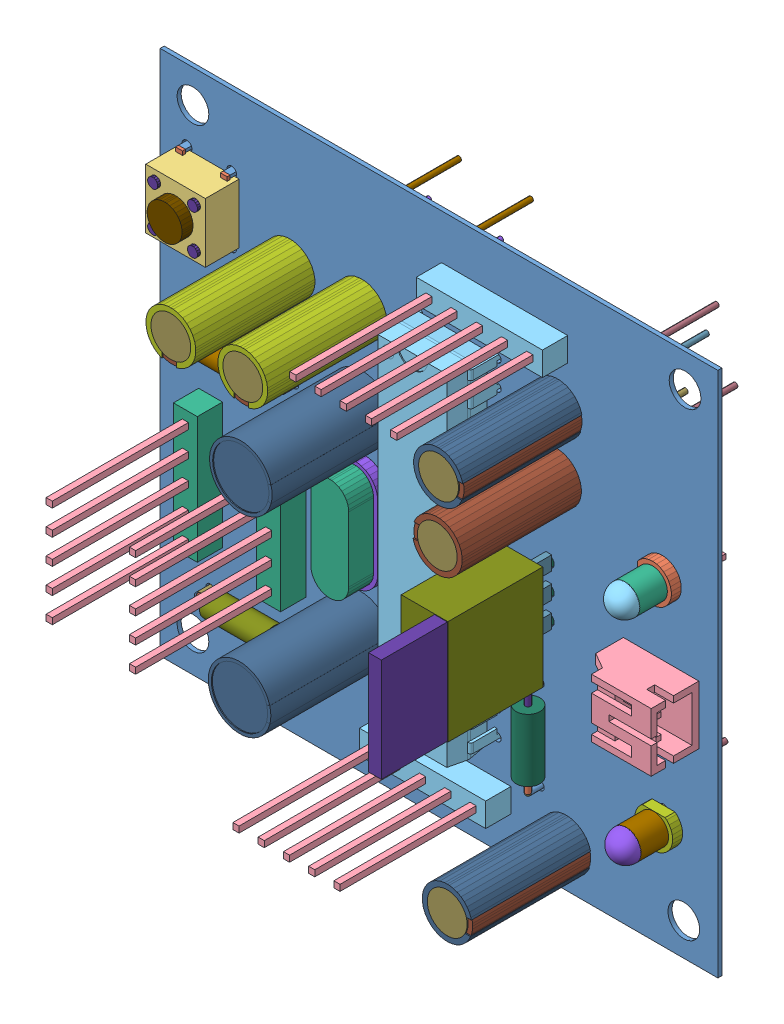
SolidWorks assembly project_1, configuration Default. Lengths in mm.
Overall size (56.13 52.96 36.7).
255 component instances, 53 part files, 0 mates.
Components (placement in the parent):
- project_1.step-1: project_1.step [Default] at origin size (56.13 52.96 36.7)
  - Board.step-1: Board.step [Default] at origin size (56.13 52.96 0.41)
    - Open CASCADE STEP translator 7.5 1.1.1.step-1: Open CASCADE STEP translator 7.5 1.1.1.step [Default] at (0 0 -0.4115) size (56.13 52.96 0.41)
  - LED-BT.step-1: LED-BT.step [Default] at origin size (3.42 3.82 10.3)
    - 6102661152.step-1: 6102661152.step [Default] at (50.736 32.131 0) size (3.42 3.82 1)
      - Extruded.step-1: Extruded.step [Default] at origin size (3.42 3.82 1)
    - 6102654272.step-1: 6102654272.step [Default] at (49.4059 32.1309 -4) size (0.5 0.5 4)
      - Extruded-0.step-1: Extruded-0.step [Default] at origin size (0.5 0.5 4)
    - 6102665392.step-1: 6102665392.step [Default] at (51.6859 32.1309 -5) size (0.5 0.5 5)
      - Extruded-1.step-1: Extruded-1.step [Default] at origin size (0.5 0.5 5)
    - 6102654592.step-1: 6102654592.step [Default] at (50.5459 32.131 3.8) x (-1 0 0) z (0 0 1) size (3 3 3)
      - Sphere.step-1: Sphere.step [Default] at origin size (3 3 3)
    - 6102659712.step-1: 6102659712.step [Default] at (50.5459 32.1309 1) x (-1 0 0) z (0 0 1) size (3 3 2.8)
      - Cylinder.step-1: Cylinder.step [Default] at origin size (3 3 2.8)
  - Buzzer.step-1: Buzzer.step [Default] at origin size (3.82 3.42 10.3)
    - 6102655392.step-1: 6102655392.step [Default] at (50.673 10.605 0) size (3.82 3.42 1)
      - Extruded-2.step-1: Extruded-2.step [Default] at origin size (3.82 3.42 1)
    - 6102654272.step-1: 6102654272.step [Default] at (50.6729 11.9351 -4) size (0.5 0.5 4)
      - Extruded-0.step-1: Extruded-0.step [Default] at origin size (0.5 0.5 4)
    - 6102665392.step-1: 6102665392.step [Default] at (50.6729 9.6551 -5) size (0.5 0.5 5)
      - Extruded-1.step-1: Extruded-1.step [Default] at origin size (0.5 0.5 5)
    - 6102665072.step-1: 6102665072.step [Default] at (50.673 10.7951 3.8) x (0 1 0) z (0 0 1) size (3 3 3)
      - Sphere-3.step-1: Sphere-3.step [Default] at origin size (3 3 3)
    - 6102664912.step-1: 6102664912.step [Default] at (50.6729 10.7951 1) x (0 1 0) z (0 0 1) size (3 3 2.8)
      - Cylinder-4.step-1: Cylinder-4.step [Default] at origin size (3 3 2.8)
  - C10.step-1: C10.step [Default] at origin size (4.95 5 29.01)
    - 6102661072.step-1: 6102661072.step [Default] at (40.8605 4.064 0.01) size (4.94 5 12)
      - Extruded-5.step-1: Extruded-5.step [Default] at origin size (4.94 5 12)
    - 6102666112.step-1: 6102666112.step [Default] at (40.894 4.064 0.02) size (4.9 4.9 11.87)
      - Extruded-6.step-1: Extruded-6.step [Default] at origin size (4.9 4.9 11.87)
    - 6102655472.step-1: 6102655472.step [Default] at (40.8939 4.0639 0) size (4 4 12)
      - Extruded-7.step-1: Extruded-7.step [Default] at origin size (4 4 12)
    - 6102661632.step-1: 6102661632.step [Default] at (39.8941 4.0641 -17) x (1 0 0) z (0 0 1) size (0.5 0.5 17)
      - Cylinder-8.step-1: Cylinder-8.step [Default] at origin size (0.5 0.5 17)
    - 6102653872.step-1: 6102653872.step [Default] at (41.8941 4.0641 -14) x (1 0 0) z (0 0 1) size (0.5 0.5 14)
      - Cylinder-9.step-1: Cylinder-9.step [Default] at origin size (0.5 0.5 14)
  - R5.step-1: R5.step [Default] at origin size (2.4 9.55 4.4)
    - 6102655552.step-1: 6102655552.step [Default] at (38.2269 15.4689 1.2) x (1 0 0) z (0 -1 0) size (2.4 2.4 6.3)
      - Cylinder-10.step-1: Cylinder-10.step [Default] at origin size (2.4 2.4 6.3)
    - 6102659232.step-1: 6102659232.step [Default] at (38.227 16.819 1.2) x (0 -1 0) z (0 0 1) size (0.55 0.55 0.55)
      - Sphere-11.step-1: Sphere-11.step [Default] at origin size (0.55 0.55 0.55)
    - 6102664992.step-1: 6102664992.step [Default] at (38.2268 16.8192 1.2) x (0 0 -1) z (0 -1 0) size (0.55 0.55 1.35)
      - Cylinder-12.step-1: Cylinder-12.step [Default] at origin size (0.55 0.55 1.35)
    - 6102653712.step-1: 6102653712.step [Default] at (38.2268 16.8192 -2) x (0 -1 0) z (0 0 1) size (0.55 0.55 3.2)
      - Cylinder-13.step-1: Cylinder-13.step [Default] at origin size (0.55 0.55 3.2)
    - 6102659872.step-1: 6102659872.step [Default] at (38.2272 7.8189 -2) x (0 1 0) z (0 0 1) size (0.55 0.55 3.2)
      - Cylinder-14.step-1: Cylinder-14.step [Default] at origin size (0.55 0.55 3.2)
    - 6102653392.step-1: 6102653392.step [Default] at (38.2272 7.8189 1.2) x (0 0 -1) z (0 1 0) size (0.55 0.55 1.35)
      - Cylinder-15.step-1: Cylinder-15.step [Default] at origin size (0.55 0.55 1.35)
    - 6102659072.step-1: 6102659072.step [Default] at (38.227 7.819 1.2) x (0 1 0) z (0 0 1) size (0.55 0.55 0.55)
      - Sphere-16.step-1: Sphere-16.step [Default] at origin size (0.55 0.55 0.55)
  - HC-SR04-3.step-1: HC-SR04-3.step [Default] at origin size (12.7 2.4 19.29)
    - 6102658592.step-1: 6102658592.step [Default] at (23.8759 5.0799 -3.05) size (0.62 0.62 19.29)
      - Extruded-17.step-1: Extruded-17.step [Default] at origin size (0.62 0.62 19.29)
    - 6102658592.step-2: 6102658592.step [Default] at (26.4159 5.0799 -3.05) size (0.62 0.62 19.29)
      - Extruded-17.step-1: Extruded-17.step [Default] at origin size (0.62 0.62 19.29)
    - 6102658592.step-3: 6102658592.step [Default] at (34.0359 5.0799 -3.05) size (0.62 0.62 19.29)
      - Extruded-17.step-1: Extruded-17.step [Default] at origin size (0.62 0.62 19.29)
    - 6102658592.step-4: 6102658592.step [Default] at (31.4959 5.0799 -3.05) size (0.62 0.62 19.29)
      - Extruded-17.step-1: Extruded-17.step [Default] at origin size (0.62 0.62 19.29)
    - 6102658592.step-5: 6102658592.step [Default] at (28.956 5.08 -3.05) size (0.62 0.62 19.29)
      - Extruded-17.step-1: Extruded-17.step [Default] at origin size (0.62 0.62 19.29)
    - 6102655632.step-1: 6102655632.step [Default] at (28.956 5.08 0) size (12.7 2.4 2.54)
      - Extruded-18.step-1: Extruded-18.step [Default] at origin size (12.7 2.4 2.54)
  - HC-SR04-2.step-1: HC-SR04-2.step [Default] at origin size (12.7 2.4 19.29)
    - 6102658592.step-1: 6102658592.step [Default] at (39.7511 47.2441 -3.05) size (0.62 0.62 19.29)
      - Extruded-17.step-1: Extruded-17.step [Default] at origin size (0.62 0.62 19.29)
    - 6102658592.step-2: 6102658592.step [Default] at (37.2111 47.2441 -3.05) size (0.62 0.62 19.29)
      - Extruded-17.step-1: Extruded-17.step [Default] at origin size (0.62 0.62 19.29)
    - 6102658592.step-3: 6102658592.step [Default] at (29.5911 47.2441 -3.05) size (0.62 0.62 19.29)
      - Extruded-17.step-1: Extruded-17.step [Default] at origin size (0.62 0.62 19.29)
    - 6102658592.step-4: 6102658592.step [Default] at (32.1311 47.2441 -3.05) size (0.62 0.62 19.29)
      - Extruded-17.step-1: Extruded-17.step [Default] at origin size (0.62 0.62 19.29)
    - 6102658592.step-5: 6102658592.step [Default] at (34.671 47.244 -3.05) size (0.62 0.62 19.29)
      - Extruded-17.step-1: Extruded-17.step [Default] at origin size (0.62 0.62 19.29)
    - 6102655632.step-1: 6102655632.step [Default] at (34.671 47.244 0) size (12.7 2.4 2.54)
      - Extruded-18.step-1: Extruded-18.step [Default] at origin size (12.7 2.4 2.54)
  - Y.step-1: Y.step [Default] at origin size (4.65 11.05 17)
    - 6102661872.step-1: 6102661872.step [Default] at (20.574 22.2619 0) size (3.8 10.35 3.5)
      - Extruded-19.step-1: Extruded-19.step [Default] at origin size (3.8 10.35 3.5)
    - 6102648432.step-1: 6102648432.step [Default] at (20.5739 19.8121 -13.5) x (0 1 0) z (0 0 1) size (0.45 0.45 13.5)
      - Cylinder-20.step-1: Cylinder-20.step [Default] at origin size (0.45 0.45 13.5)
    - 6102648432.step-2: 6102648432.step [Default] at (20.5739 24.7121 -13.5) x (0 1 0) z (0 0 1) size (0.45 0.45 13.5)
      - Cylinder-20.step-1: Cylinder-20.step [Default] at origin size (0.45 0.45 13.5)
    - 6102647952.step-1: 6102647952.step [Default] at (20.574 22.2619 0) size (4.65 11.05 1)
      - Extruded-21.step-1: Extruded-21.step [Default] at origin size (4.65 11.05 1)
  - R4.step-1: R4.step [Default] at origin size (9.55 2.4 4.4)
    - 6102655152.step-1: 6102655152.step [Default] at (5.8671 30.4799 1.2) x (0 1 0) z (1 0 0) size (2.4 2.4 6.3)
      - Cylinder-22.step-1: Cylinder-22.step [Default] at origin size (2.4 2.4 6.3)
    - 6102653312.step-1: 6102653312.step [Default] at (4.517 30.48 1.2) x (1 0 0) z (0 0 1) size (0.55 0.55 0.55)
      - Sphere-23.step-1: Sphere-23.step [Default] at origin size (0.55 0.55 0.55)
    - 6102664512.step-1: 6102664512.step [Default] at (4.5169 30.4798 1.2) x (0 0 -1) z (1 0 0) size (0.55 0.55 1.35)
      - Cylinder-24.step-1: Cylinder-24.step [Default] at origin size (0.55 0.55 1.35)
    - 6102659152.step-1: 6102659152.step [Default] at (4.5169 30.4798 -2) x (1 0 0) z (0 0 1) size (0.55 0.55 3.2)
      - Cylinder-25.step-1: Cylinder-25.step [Default] at origin size (0.55 0.55 3.2)
    - 6102660352.step-1: 6102660352.step [Default] at (13.5171 30.4802 -2) x (-1 0 0) z (0 0 1) size (0.55 0.55 3.2)
      - Cylinder-26.step-1: Cylinder-26.step [Default] at origin size (0.55 0.55 3.2)
    - 6102658992.step-1: 6102658992.step [Default] at (13.5171 30.4802 1.2) x (0 0 -1) z (-1 0 0) size (0.55 0.55 1.35)
      - Cylinder-27.step-1: Cylinder-27.step [Default] at origin size (0.55 0.55 1.35)
    - 6102664672.step-1: 6102664672.step [Default] at (13.517 30.48 1.2) x (-1 0 0) z (0 0 1) size (0.55 0.55 0.55)
      - Sphere-28.step-1: Sphere-28.step [Default] at origin size (0.55 0.55 0.55)
  - R3.step-1: R3.step [Default] at origin size (9.55 2.4 4.4)
    - 6102653312.step-1: 6102653312.step [Default] at (5.025 8.382 1.2) x (1 0 0) z (0 0 1) size (0.55 0.55 0.55)
      - Sphere-23.step-1: Sphere-23.step [Default] at origin size (0.55 0.55 0.55)
    - 6102664512.step-1: 6102664512.step [Default] at (5.0249 8.3818 1.2) x (0 0 -1) z (1 0 0) size (0.55 0.55 1.35)
      - Cylinder-24.step-1: Cylinder-24.step [Default] at origin size (0.55 0.55 1.35)
    - 6102659152.step-1: 6102659152.step [Default] at (5.0249 8.3818 -2) x (1 0 0) z (0 0 1) size (0.55 0.55 3.2)
      - Cylinder-25.step-1: Cylinder-25.step [Default] at origin size (0.55 0.55 3.2)
    - 6102660352.step-1: 6102660352.step [Default] at (14.0251 8.3822 -2) x (-1 0 0) z (0 0 1) size (0.55 0.55 3.2)
      - Cylinder-26.step-1: Cylinder-26.step [Default] at origin size (0.55 0.55 3.2)
    - 6102658992.step-1: 6102658992.step [Default] at (14.0251 8.3822 1.2) x (0 0 -1) z (-1 0 0) size (0.55 0.55 1.35)
      - Cylinder-27.step-1: Cylinder-27.step [Default] at origin size (0.55 0.55 1.35)
    - 6102664672.step-1: 6102664672.step [Default] at (14.025 8.382 1.2) x (-1 0 0) z (0 0 1) size (0.55 0.55 0.55)
      - Sphere-28.step-1: Sphere-28.step [Default] at origin size (0.55 0.55 0.55)
    - 6102662752.step-1: 6102662752.step [Default] at (12.6749 8.3821 1.2) x (0 -1 0) z (-1 0 0) size (2.4 2.4 6.3)
      - Cylinder-29.step-1: Cylinder-29.step [Default] at origin size (2.4 2.4 6.3)
  - R1.step-1: R1.step [Default] at origin size (9.55 2.4 4.4)
    - 6102664672.step-1: 6102664672.step [Default] at (13.517 34.671 1.2) x (-1 0 0) z (0 0 1) size (0.55 0.55 0.55)
      - Sphere-28.step-1: Sphere-28.step [Default] at origin size (0.55 0.55 0.55)
    - 6102658992.step-1: 6102658992.step [Default] at (13.5171 34.6712 1.2) x (0 0 -1) z (-1 0 0) size (0.55 0.55 1.35)
      - Cylinder-27.step-1: Cylinder-27.step [Default] at origin size (0.55 0.55 1.35)
    - 6102660352.step-1: 6102660352.step [Default] at (13.5171 34.6712 -2) x (-1 0 0) z (0 0 1) size (0.55 0.55 3.2)
      - Cylinder-26.step-1: Cylinder-26.step [Default] at origin size (0.55 0.55 3.2)
    - 6102659152.step-1: 6102659152.step [Default] at (4.5169 34.6708 -2) x (1 0 0) z (0 0 1) size (0.55 0.55 3.2)
      - Cylinder-25.step-1: Cylinder-25.step [Default] at origin size (0.55 0.55 3.2)
    - 6102664512.step-1: 6102664512.step [Default] at (4.5169 34.6708 1.2) x (0 0 -1) z (1 0 0) size (0.55 0.55 1.35)
      - Cylinder-24.step-1: Cylinder-24.step [Default] at origin size (0.55 0.55 1.35)
    - 6102653312.step-1: 6102653312.step [Default] at (4.517 34.671 1.2) x (1 0 0) z (0 0 1) size (0.55 0.55 0.55)
      - Sphere-23.step-1: Sphere-23.step [Default] at origin size (0.55 0.55 0.55)
    - 6102655152.step-1: 6102655152.step [Default] at (5.8671 34.6709 1.2) x (0 1 0) z (1 0 0) size (2.4 2.4 6.3)
      - Cylinder-22.step-1: Cylinder-22.step [Default] at origin size (2.4 2.4 6.3)
  - Push button.step-1: Push button.step [Default] at origin size (6 6.8 8)
    - 6102654192.step-1: 6102654192.step [Default] at (2.953 40.545 0.1) size (1 1 3.6)
      - Extruded-30.step-1: Extruded-30.step [Default] at origin size (1 1 3.6)
    - 6102654192.step-2: 6102654192.step [Default] at (6.953 44.545 0.1) size (1 1 3.6)
      - Extruded-30.step-1: Extruded-30.step [Default] at origin size (1 1 3.6)
    - 6102654192.step-3: 6102654192.step [Default] at (6.953 40.545 0.1) size (1 1 3.6)
      - Extruded-30.step-1: Extruded-30.step [Default] at origin size (1 1 3.6)
    - 6102654192.step-4: 6102654192.step [Default] at (2.953 44.545 0.1) size (1 1 3.6)
      - Extruded-30.step-1: Extruded-30.step [Default] at origin size (1 1 3.6)
    - 6102662512.step-1: 6102662512.step [Default] at (4.9531 42.5449 0.1) size (3.5 3.5 4.4)
      - Extruded-31.step-1: Extruded-31.step [Default] at origin size (3.5 3.5 4.4)
    - 6102656752.step-1: 6102656752.step [Default] at (2.7031 45.7951 -3.5) size (0.7 0.3 4)
      - Extruded-32.step-1: Extruded-32.step [Default] at origin size (0.7 0.3 4)
    - 6102654672.step-1: 6102654672.step [Default] at (2.7031 45.6455 0.5) size (0.7 0.6 0.3)
      - Extruded-33.step-1: Extruded-33.step [Default] at origin size (0.7 0.6 0.3)
    - 6102656752.step-2: 6102656752.step [Default] at (7.2029 39.2949 -3.5) size (0.7 0.3 4)
      - Extruded-32.step-1: Extruded-32.step [Default] at origin size (0.7 0.3 4)
    - 6102654672.step-2: 6102654672.step [Default] at (7.2029 39.4445 0.5) size (0.7 0.6 0.3)
      - Extruded-33.step-1: Extruded-33.step [Default] at origin size (0.7 0.6 0.3)
    - 6102656752.step-3: 6102656752.step [Default] at (7.2029 45.7951 -3.5) size (0.7 0.3 4)
      - Extruded-32.step-1: Extruded-32.step [Default] at origin size (0.7 0.3 4)
    - 6102654672.step-3: 6102654672.step [Default] at (7.2029 45.6455 0.5) size (0.7 0.6 0.3)
      - Extruded-33.step-1: Extruded-33.step [Default] at origin size (0.7 0.6 0.3)
    - 6102654672.step-4: 6102654672.step [Default] at (2.7031 39.4445 0.5) size (0.7 0.6 0.3)
      - Extruded-33.step-1: Extruded-33.step [Default] at origin size (0.7 0.6 0.3)
    - 6102656752.step-4: 6102656752.step [Default] at (2.7031 39.2949 -3.5) size (0.7 0.3 4)
      - Extruded-32.step-1: Extruded-32.step [Default] at origin size (0.7 0.3 4)
    - 6102660032.step-1: 6102660032.step [Default] at (4.953 42.545 0) size (6 6 3.4)
      - Extruded-34.step-1: Extruded-34.step [Default] at origin size (6 6 3.4)
  - POWER.step-1: POWER.step [Default] at origin size (7.6 5.9 8.2)
    - S2B-PH-K-S.step-1: S2B-PH-K-S.step [Default] at (45.2688 29.7212 6) x (0 1 0) z (1 0 0) size (5.9 8.2 7.6)
  - Microcontroller.step-1: Microcontroller.step [Default] at origin size (7.9 34.67 8)
    - 6105365808.step-1: 6105365808.step [Default] at (29.972 26.416 0) x (1 0 0) z (0 -1 0) size (7.9 8 34.67)
  - HC-SR04-1.step-1: HC-SR04-1.step [Default] at origin size (2.4 12.7 19.29)
    - 6102658192.step-1: 6102658192.step [Default] at (13.462 18.796 0) size (2.4 12.7 2.54)
      - Extruded-35.step-1: Extruded-35.step [Default] at origin size (2.4 12.7 2.54)
    - 6102658592.step-1: 6102658592.step [Default] at (13.462 18.796 -3.05) size (0.62 0.62 19.29)
      - Extruded-17.step-1: Extruded-17.step [Default] at origin size (0.62 0.62 19.29)
    - 6102658592.step-2: 6102658592.step [Default] at (13.4621 21.3359 -3.05) size (0.62 0.62 19.29)
      - Extruded-17.step-1: Extruded-17.step [Default] at origin size (0.62 0.62 19.29)
    - 6102658592.step-3: 6102658592.step [Default] at (13.4621 23.8759 -3.05) size (0.62 0.62 19.29)
      - Extruded-17.step-1: Extruded-17.step [Default] at origin size (0.62 0.62 19.29)
    - 6102658592.step-4: 6102658592.step [Default] at (13.4621 16.2559 -3.05) size (0.62 0.62 19.29)
      - Extruded-17.step-1: Extruded-17.step [Default] at origin size (0.62 0.62 19.29)
    - 6102658592.step-5: 6102658592.step [Default] at (13.4621 13.7159 -3.05) size (0.62 0.62 19.29)
      - Extruded-17.step-1: Extruded-17.step [Default] at origin size (0.62 0.62 19.29)
  - HC-05.step-1: HC-05.step [Default] at origin size (2.4 12.7 19.29)
    - 6102658192.step-1: 6102658192.step [Default] at (5.08 18.923 0) size (2.4 12.7 2.54)
      - Extruded-35.step-1: Extruded-35.step [Default] at origin size (2.4 12.7 2.54)
    - 6102658592.step-1: 6102658592.step [Default] at (5.08 18.923 -3.05) size (0.62 0.62 19.29)
      - Extruded-17.step-1: Extruded-17.step [Default] at origin size (0.62 0.62 19.29)
    - 6102658592.step-2: 6102658592.step [Default] at (5.0801 21.4629 -3.05) size (0.62 0.62 19.29)
      - Extruded-17.step-1: Extruded-17.step [Default] at origin size (0.62 0.62 19.29)
    - 6102658592.step-3: 6102658592.step [Default] at (5.0801 24.0029 -3.05) size (0.62 0.62 19.29)
      - Extruded-17.step-1: Extruded-17.step [Default] at origin size (0.62 0.62 19.29)
    - 6102658592.step-4: 6102658592.step [Default] at (5.0801 16.3829 -3.05) size (0.62 0.62 19.29)
      - Extruded-17.step-1: Extruded-17.step [Default] at origin size (0.62 0.62 19.29)
    - 6102658592.step-5: 6102658592.step [Default] at (5.0801 13.8429 -3.05) size (0.62 0.62 19.29)
      - Extruded-17.step-1: Extruded-17.step [Default] at origin size (0.62 0.62 19.29)
  - C8.step-1: C8.step [Default] at origin size (5 4.95 29.01)
    - 6102655472.step-1: 6102655472.step [Default] at (20.3199 40.4971 0) size (4 4 12)
      - Extruded-7.step-1: Extruded-7.step [Default] at origin size (4 4 12)
    - 6102666112.step-1: 6102666112.step [Default] at (20.32 40.497 0.02) size (4.9 4.9 11.87)
      - Extruded-6.step-1: Extruded-6.step [Default] at origin size (4.9 4.9 11.87)
    - 6102665232.step-1: 6102665232.step [Default] at (20.32 40.5305 0.01) size (5 4.94 12)
      - Extruded-36.step-1: Extruded-36.step [Default] at origin size (5 4.94 12)
    - 6102665152.step-1: 6102665152.step [Default] at (20.3201 39.4969 -14) x (0 -1 0) z (0 0 1) size (0.5 0.5 14)
      - Cylinder-37.step-1: Cylinder-37.step [Default] at origin size (0.5 0.5 14)
    - 6102655952.step-1: 6102655952.step [Default] at (20.3201 41.4969 -17) x (0 -1 0) z (0 0 1) size (0.5 0.5 17)
      - Cylinder-38.step-1: Cylinder-38.step [Default] at origin size (0.5 0.5 17)
  - C5.step-1: C5.step [Default] at origin size (4.95 5 29.01)
    - 6102655472.step-1: 6102655472.step [Default] at (40.0209 41.6559 0) size (4 4 12)
      - Extruded-7.step-1: Extruded-7.step [Default] at origin size (4 4 12)
    - 6102666112.step-1: 6102666112.step [Default] at (40.021 41.656 0.02) size (4.9 4.9 11.87)
      - Extruded-6.step-1: Extruded-6.step [Default] at origin size (4.9 4.9 11.87)
    - 6102661072.step-1: 6102661072.step [Default] at (39.9875 41.656 0.01) size (4.94 5 12)
      - Extruded-5.step-1: Extruded-5.step [Default] at origin size (4.94 5 12)
    - 6102653872.step-1: 6102653872.step [Default] at (41.0211 41.6561 -14) x (1 0 0) z (0 0 1) size (0.5 0.5 14)
      - Cylinder-9.step-1: Cylinder-9.step [Default] at origin size (0.5 0.5 14)
    - 6102661632.step-1: 6102661632.step [Default] at (39.0211 41.6561 -17) x (1 0 0) z (0 0 1) size (0.5 0.5 17)
      - Cylinder-8.step-1: Cylinder-8.step [Default] at origin size (0.5 0.5 17)
  - C4.step-1: C4.step [Default] at origin size (5 4.95 29.01)
    - 6102665232.step-1: 6102665232.step [Default] at (13.081 40.4195 0.01) size (5 4.94 12)
      - Extruded-36.step-1: Extruded-36.step [Default] at origin size (5 4.94 12)
    - 6102666112.step-1: 6102666112.step [Default] at (13.081 40.386 0.02) size (4.9 4.9 11.87)
      - Extruded-6.step-1: Extruded-6.step [Default] at origin size (4.9 4.9 11.87)
    - 6102655472.step-1: 6102655472.step [Default] at (13.0809 40.3861 0) size (4 4 12)
      - Extruded-7.step-1: Extruded-7.step [Default] at origin size (4 4 12)
    - 6102655952.step-1: 6102655952.step [Default] at (13.0811 41.3859 -17) x (0 -1 0) z (0 0 1) size (0.5 0.5 17)
      - Cylinder-38.step-1: Cylinder-38.step [Default] at origin size (0.5 0.5 17)
    - 6102665152.step-1: 6102665152.step [Default] at (13.0811 39.3859 -14) x (0 -1 0) z (0 0 1) size (0.5 0.5 14)
      - Cylinder-37.step-1: Cylinder-37.step [Default] at origin size (0.5 0.5 14)
  - C3.step-1: C3.step [Default] at origin size (6.31 6.3 16.21)
    - PNSC-ECA-1VM101.step-1: PNSC-ECA-1VM101.step [Default] at (20.1931 12.5731 0) x (1 0 0) z (0 0 1) size (6.31 6.3 16.21)
  - C2.step-1: C2.step [Default] at origin size (6.31 6.3 16.21)
    - PNSC-ECA-1VM101.step-1: PNSC-ECA-1VM101.step [Default] at (20.3201 31.8771 0) x (1 0 0) z (0 0 1) size (6.31 6.3 16.21)
  - C1.step-1: C1.step [Default] at origin size (4.95 5 29.01)
    - 6102655472.step-1: 6102655472.step [Default] at (39.8941 35.5601 0) size (4 4 12)
      - Extruded-7.step-1: Extruded-7.step [Default] at origin size (4 4 12)
    - 6102666112.step-1: 6102666112.step [Default] at (39.894 35.56 0.02) size (4.9 4.9 11.87)
      - Extruded-6.step-1: Extruded-6.step [Default] at origin size (4.9 4.9 11.87)
    - 6102658112.step-1: 6102658112.step [Default] at (39.9275 35.56 0.01) size (4.94 5 12)
      - Extruded-39.step-1: Extruded-39.step [Default] at origin size (4.94 5 12)
    - 6102659952.step-1: 6102659952.step [Default] at (38.8939 35.5599 -14) x (-1 0 0) z (0 0 1) size (0.5 0.5 14)
      - Cylinder-40.step-1: Cylinder-40.step [Default] at origin size (0.5 0.5 14)
    - 6102664592.step-1: 6102664592.step [Default] at (40.8939 35.5599 -17) x (-1 0 0) z (0 0 1) size (0.5 0.5 17)
      - Cylinder-41.step-1: Cylinder-41.step [Default] at origin size (0.5 0.5 17)
  - 5V regulator.step-1: 5V regulator.step [Default] at origin size (4.7 10.5 29.7)
    - 6102663872.step-1: 6102663872.step [Default] at (39.1161 22.7329 0) size (0.59 1.42 3.5)
      - Extruded-42.step-1: Extruded-42.step [Default] at origin size (0.59 1.42 3.5)
    - 6102654032.step-1: 6102654032.step [Default] at (39.116 22.733 -10) size (0.59 0.75 13.5)
      - Extruded-43.step-1: Extruded-43.step [Default] at origin size (0.59 0.75 13.5)
    - 6102663872.step-2: 6102663872.step [Default] at (39.1161 27.8129 0) size (0.59 1.42 3.5)
      - Extruded-42.step-1: Extruded-42.step [Default] at origin size (0.59 1.42 3.5)
    - 6102654032.step-2: 6102654032.step [Default] at (39.116 27.813 -10) size (0.59 0.75 13.5)
      - Extruded-43.step-1: Extruded-43.step [Default] at origin size (0.59 0.75 13.5)
    - 6102654032.step-3: 6102654032.step [Default] at (39.116 25.273 -10) size (0.59 0.75 13.5)
      - Extruded-43.step-1: Extruded-43.step [Default] at origin size (0.59 0.75 13.5)
    - 6102663872.step-3: 6102663872.step [Default] at (39.116 25.273 0) size (0.59 1.42 3.5)
      - Extruded-42.step-1: Extruded-42.step [Default] at origin size (0.59 1.42 3.5)
    - 6102657392.step-1: 6102657392.step [Default] at (39.666 25.273 3.5) size (4.7 10.5 9.55)
      - Extruded-44.step-1: Extruded-44.step [Default] at origin size (4.7 10.5 9.55)
    - 6102663552.step-1: 6102663552.step [Default] at (41.316 25.273 13.05) size (1.3 10.4 6.65)
      - Extruded-45.step-1: Extruded-45.step [Default] at origin size (1.3 10.4 6.65)
